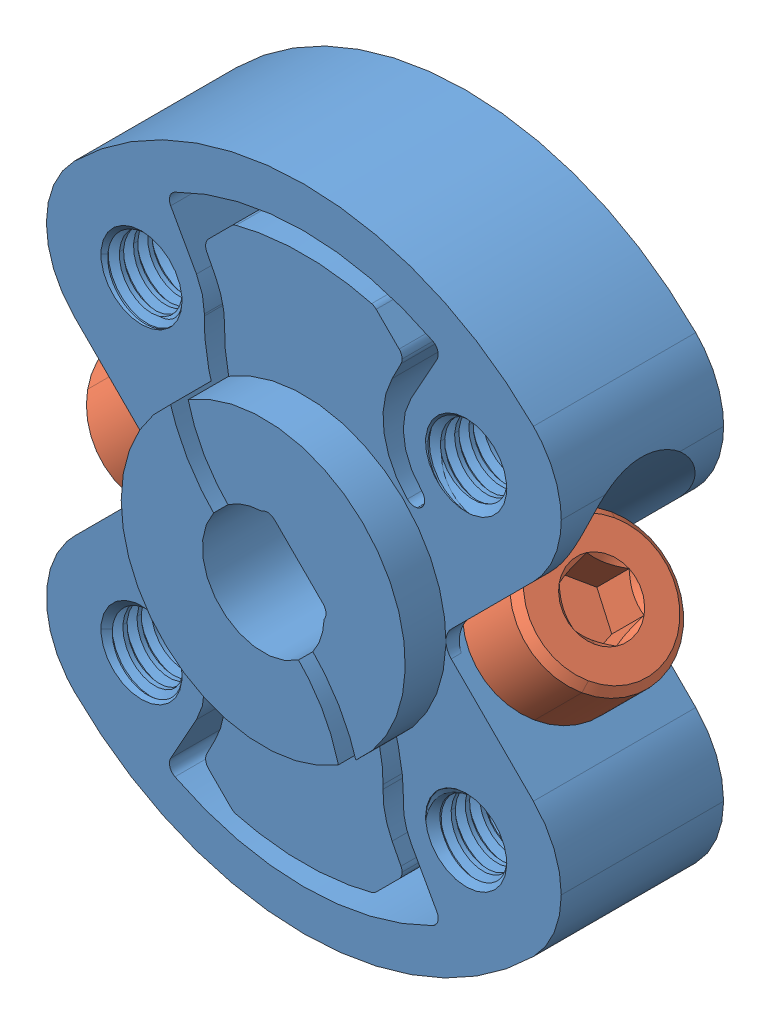
SolidWorks assembly 1309-0016-1006 assembly, configuration Default. Lengths in mm.
Overall size (28.36 32 10.95).
4 component instances, 2 part files, 0 mates.
Components (placement in the parent):
- 1309-0016-1006 assembly.STEP-1: 1309-0016-1006 assembly.STEP [Default] at origin size (28.36 32 10.95)
  - 1309-0016-1006.STEP-1: 1309-0016-1006.STEP [Default] at (-18.2019 0.5776 8.7736) size (25.38 32 10)
  - 2800-0004-0014_90128A207.STEP-1: 2800-0004-0014_90128A207.STEP [Default] at (-16.149 11.6963 8.7736) x (0.5 -0.5 -0.707107) z (0.707107 0.707107 0) size (7 7 18.01)
  - 2800-0004-0014_90128A207.STEP-2: 2800-0004-0014_90128A207.STEP [Default] at (-20.2547 -10.5411 8.7736) x (-0.5 0.5 -0.707107) z (-0.707107 -0.707107 0) size (7 7 18.01)
